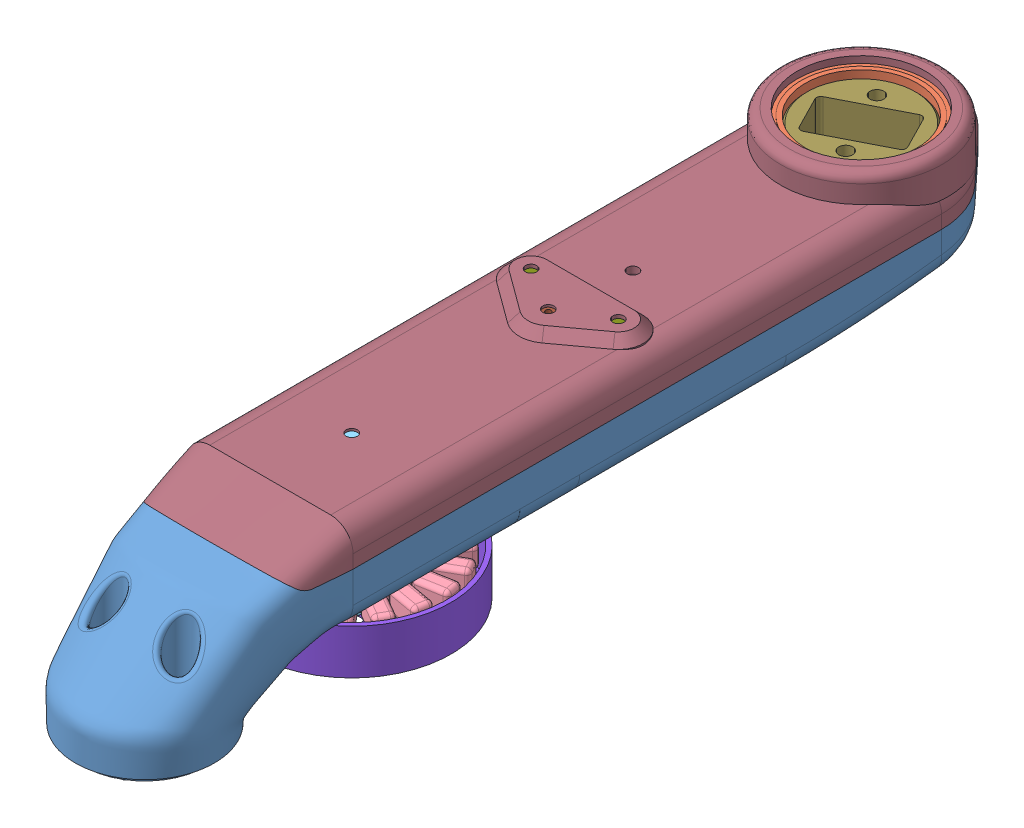
SolidWorks assembly actuator core assembly, configuration Default. Lengths in mm.
Overall size (62.38 43.94 198.25).
27 component instances, 16 part files, 38 mates.
Components (placement in the parent):
- upper limb base-1: upper limb base [Default] at (70.7092 92.7911 149.0007) size (42.52 37.51 198.25)
  - upper leg module shell base-1: upper leg module shell base [Default] x (-1 0 0) z (0 0 -1) size (37.02 37.51 198.25)
  - bearing 32x25x4mm-1: bearing 32x25x4mm [Default] at (0 0.5 -61) x (0.90658 0 0.422034) z (-0.422034 0 0.90658) size (32 4 32)
  - bearing 8mm x 3mm x 3mm-1: bearing 8mm x 3mm x 3mm [Default] at (0 -1.5 8.9) x (1 0 0) z (0 -1 0) size (7.96 7.96 3)
- motor rotor-1: motor rotor [Default] at (70.7092 85.0911 201.8007) x (0 0 -1) z (-1 0 0) size (40 13.5 39.72)
- motor assembly-2: motor assembly [Default] at (70.7092 72.4911 201.8007) x (-0.761097 0 -0.648639) z (-0.648639 0 0.761097) size (16.67 33.4 16.67)
  - motor shaft-1: motor shaft [Default] x (1 0 0) z (0 -1 0) size (3.99 3.99 33.4)
  - motor pulley-1: motor pulley [Default] at (0 -20.1 0) x (1 0 0) z (0 -1 0) size (8.98 9.1 6.7)
  - encoder wheel mount-1: encoder wheel mount [Default] at (0 -28.3 0) x (-0.562764 0 0.826618) z (-0.826618 0 -0.562764) size (12 5.96 12)
- motor stator-1: motor stator [Default] at (70.7092 85.0911 201.8007) x (0.629554 0 -0.776957) z (0 -1 0) size (44.35 44.35 16.24)
- B18.6.7M - M3 x 0.5 x 5 Type I Cross Recessed FHMS --5S-1: B18.6.7M - M3 x 0.5 x 5 Type I Cross Recessed FHMS --5S [B18.6.7M - M3 x 0.5 x 5 Type I Cross Recessed FHMS --5S] at (83.2092 94.5911 201.8007) x (0 -1 0) z (-0.166423 0 0.986054) size (5 5.5 5.5)
- B18.6.7M - M3 x 0.5 x 5 Type I Cross Recessed FHMS --5S-2: B18.6.7M - M3 x 0.5 x 5 Type I Cross Recessed FHMS --5S [B18.6.7M - M3 x 0.5 x 5 Type I Cross Recessed FHMS --5S] at (70.7092 94.5911 214.3007) x (0 -1 0) z (0.029806 0 0.999556) size (5 5.5 5.5)
- B18.6.7M - M3 x 0.5 x 5 Type I Cross Recessed FHMS --5S-3: B18.6.7M - M3 x 0.5 x 5 Type I Cross Recessed FHMS --5S [B18.6.7M - M3 x 0.5 x 5 Type I Cross Recessed FHMS --5S] at (58.2092 94.5911 201.8007) x (0 -1 0) z (0.999629 0 -0.027231) size (5 5.5 5.5)
- B18.6.7M - M3 x 0.5 x 5 Type I Cross Recessed FHMS --5S-4: B18.6.7M - M3 x 0.5 x 5 Type I Cross Recessed FHMS --5S [B18.6.7M - M3 x 0.5 x 5 Type I Cross Recessed FHMS --5S] at (70.7092 94.5911 189.3007) x (0 -1 0) z (-0.93368 0 0.358107) size (5 5.5 5.5)
- centre pulley-1: centre pulley [Default] at (66.4357 80.4446 131.9015) x (0.990944 0 0.134278) z (-0.134278 0 0.990944) size (30 19 30)
  - transmission pulley centre-1: transmission pulley centre [Default] at (7.726 11.8465 25.1899) size (30 6.8 30)
  - centre pulley-1: centre pulley [Default] at (7.726 25.3465 25.1899) x (0.694658 0 -0.71934) z (0 -1 0) size (8.98 9.1 19)
- transmission pulley output-1: transmission pulley output [Default] at (70.7092 97.7911 88.0007) x (-0.454924 0 -0.89053) z (0.89053 0 -0.454924) size (29 16.4 29)
- upper leg module cover-1: upper leg module cover [Default] at (70.7092 98.7911 142.6299) x (0 0 1) z (-1 0 0) size (170.23 17.96 37.06)
- bearing 32x25x4mm-1: bearing 32x25x4mm [Default] at (70.7092 107.2911 88.0007) size (32 4 32)
- bearing 8mm x 3mm x 3mm-1: bearing 8mm x 3mm x 3mm [Default] at (70.7092 107.2911 157.9007) x (1 0 0) z (0 -1 0) size (7.96 7.96 3)
- transmission belt tension roller-1: transmission belt tension roller [Default] at (60.9592 99.8911 152.0007) x (0.454066 0 0.890968) z (-0.890968 0 0.454066) size (10 4 10)
- bearing 7mm x 3mm x 3mm-2: bearing 7mm x 3mm x 3mm [Default] at (60.9592 103.8911 152.0007) x (0.030533 0 0.999534) z (0 -1 0) size (7 7 3)
- transmission belt tension roller-2: transmission belt tension roller [Default] at (80.4592 99.8911 152.0007) x (0.177081 0 -0.984196) z (0.984196 0 0.177081) size (10 4 10)
- bearing 7mm x 3mm x 3mm-3: bearing 7mm x 3mm x 3mm [Default] at (80.4592 103.8911 152.0007) x (0 0 -1) z (0 -1 0) size (7 7 3)
- flat head screw_am-1: flat head screw_am [B18.6.7M - M3 x 0.5 x 8 Type I Cross Recessed FHMS --8S] at (60.9592 100.0411 152.0007) x (0 1 0) z (0.851744 0 -0.523958) size (8 5.5 5.5)
- flat head screw_am-2: flat head screw_am [B18.6.7M - M3 x 0.5 x 8 Type I Cross Recessed FHMS --8S] at (80.4592 100.0411 152.0007) x (0 1 0) z (0.851744 0 -0.523958) size (8 5.5 5.5)
Mates (geometry in assembly coordinates):
- Concentric1: concentric aligned: cylinder of upper limb base-1/upper leg module shell base-1 through (70.7092 93.0911 201.8007) axis (0 -1 0) radius 15.25; cylinder of motor rotor-1 through (70.7092 92.5911 201.8007) axis (0 -1 0) radius 15
- Concentric2: concentric anti-aligned: cylinder of upper limb base-1/upper leg module shell base-1 through (70.7092 64.5911 189.3007) axis (0 1 0) radius 1.6; cylinder of motor rotor-1 through (70.7092 92.5911 189.3007) axis (0 -1 0) radius 2
- Coincident1: coincident anti-aligned: plane of upper limb base-1/upper leg module shell base-1 through (70.7092 92.5911 201.8007) normal (0 -1 0); plane of motor rotor-1 through (70.7092 92.5911 201.8007) normal (0 1 0)
- Concentric3: concentric aligned: line of motor rotor-1 through (70.7092 92.5911 201.8007) axis (0 -1 0); cylinder of motor assembly-2/motor shaft-1 through (70.7092 105.8911 201.8007) axis (0 -1 0) radius 1.995
- Coincident2: coincident anti-aligned: plane of motor rotor-1 through (70.7092 92.5911 201.8007) normal (0 1 0); plane of motor assembly-2/motor pulley-1 through (70.7092 92.5911 201.8007) normal (0 -1 0)
- Concentric4: concentric aligned: cylinder of motor assembly-2/motor shaft-1 through (70.7092 105.8911 201.8007) axis (0 -1 0) radius 1.995; cylinder of motor stator-1 through (70.7092 75.0911 201.8007) axis (0 -1 0) radius 2
- Coincident3: coincident aligned: plane of motor rotor-1 through (70.7092 85.0911 201.8007) normal (0 1 0); plane of motor stator-1 through (70.7092 85.0911 201.8007) normal (0 1 0)
- Concentric5: concentric anti-aligned: cylinder of motor rotor-1 through (70.7092 92.5911 189.3007) axis (0 -1 0) radius 2; cylinder of B18.6.7M - M3 x 0.5 x 5 Type I Cross Recessed FHMS --5S-4 through (70.7092 100.9411 189.3007) axis (0 1 0) radius 1.5
- Concentric6: concentric anti-aligned: cylinder of motor rotor-1 through (58.2092 92.5911 201.8007) axis (0 -1 0) radius 2; cylinder of B18.6.7M - M3 x 0.5 x 5 Type I Cross Recessed FHMS --5S-3 through (58.2092 100.9411 201.8007) axis (0 1 0) radius 1.5
- Concentric7: concentric anti-aligned: cylinder of motor rotor-1 through (70.7092 92.5911 214.3007) axis (0 -1 0) radius 2; cylinder of B18.6.7M - M3 x 0.5 x 5 Type I Cross Recessed FHMS --5S-2 through (70.7092 100.9411 214.3007) axis (0 1 0) radius 1.5
- Concentric8: concentric anti-aligned: cylinder of motor rotor-1 through (83.2092 92.5911 201.8007) axis (0 -1 0) radius 2; cylinder of B18.6.7M - M3 x 0.5 x 5 Type I Cross Recessed FHMS --5S-1 through (83.2092 100.9411 201.8007) axis (0 1 0) radius 1.5
- Coincident4: coincident aligned: plane of upper limb base-1/upper leg module shell base-1 through (70.7092 94.5911 201.8007) normal (0 1 0); plane of B18.6.7M - M3 x 0.5 x 5 Type I Cross Recessed FHMS --5S-4 through (70.7092 94.5911 189.3007) normal (0 1 0)
- Coincident5: coincident aligned: plane of upper limb base-1/upper leg module shell base-1 through (70.7092 94.5911 201.8007) normal (0 1 0); plane of B18.6.7M - M3 x 0.5 x 5 Type I Cross Recessed FHMS --5S-3 through (58.2092 94.5911 201.8007) normal (0 1 0)
- Coincident6: coincident aligned: plane of upper limb base-1/upper leg module shell base-1 through (70.7092 94.5911 201.8007) normal (0 1 0); plane of B18.6.7M - M3 x 0.5 x 5 Type I Cross Recessed FHMS --5S-1 through (83.2092 94.5911 201.8007) normal (0 1 0)
- Coincident7: coincident aligned: plane of upper limb base-1/upper leg module shell base-1 through (70.7092 94.5911 201.8007) normal (0 1 0); plane of B18.6.7M - M3 x 0.5 x 5 Type I Cross Recessed FHMS --5S-2 through (70.7092 94.5911 214.3007) normal (0 1 0)
- Concentric9: concentric anti-aligned: line of upper limb base-1/bearing 8mm x 3mm x 3mm-1 through (70.7092 91.0911 157.9007) axis (0 -1 0); cylinder of centre pulley-1/centre pulley-1 through (70.7092 89.2911 157.9007) axis (0 1 0) radius 1.995
- Coincident9: coincident anti-aligned: plane of upper limb base-1/bearing 8mm x 3mm x 3mm-1 through (70.7092 91.2911 157.9007) normal (0 1 0); plane of centre pulley-1/centre pulley-1 through (70.7092 91.2911 157.9007) normal (0 -1 0)
- Concentric11: concentric anti-aligned: cylinder of upper limb base-1/bearing 32x25x4mm-1 through (70.7092 97.2911 88.0007) axis (0 -1 0) radius 12.5; cylinder of transmission pulley output-1 through (70.7092 93.4411 88.0007) axis (0 1 0) radius 12.575
- Coincident12: coincident anti-aligned: plane of upper limb base-1/bearing 32x25x4mm-1 through (70.7092 97.2911 88.0007) normal (0 1 0); plane of transmission pulley output-1 through (70.7092 97.2911 88.0007) normal (0 -1 0)
- Concentric12: concentric aligned: circle of upper limb base-1/bearing 32x25x4mm-1; cylinder of upper leg module cover-1 through (70.7092 87.7911 88.0007) axis (0 1 0) radius 14.25
- Coincident20: coincident aligned: plane of upper limb base-1/upper leg module shell base-1 through (89.2092 86.7911 109.0007) normal (1 0 0); plane of upper leg module cover-1 through (89.2092 106.7911 219.9999) normal (1 0 0)
- Coincident24: coincident anti-aligned: plane of upper leg module cover-1 through (70.7092 107.2911 157.9007) normal (0 -1 0); plane of bearing 8mm x 3mm x 3mm-1 through (70.7092 107.2911 157.9007) normal (0 1 0)
- Concentric16: concentric anti-aligned: cylinder of upper leg module cover-1 through (70.7092 107.2911 157.9007) axis (0 -1 0) radius 3.98; cylinder of bearing 8mm x 3mm x 3mm-1 through (70.7092 104.2911 157.9007) axis (0 1 0) radius 3.98
- Concentric17: concentric anti-aligned: cylinder of upper leg module cover-1 through (70.7092 100.7911 88.0007) axis (0 1 0) radius 16.4954; cylinder of bearing 32x25x4mm-1 through (70.7092 111.2911 88.0007) axis (0 -1 0) radius 16
- Coincident25: coincident anti-aligned: plane of upper leg module cover-1 through (70.7092 111.2911 88.0007) normal (0 -1 0); plane of bearing 32x25x4mm-1 through (70.7092 111.2911 88.0007) normal (0 1 0)
- Concentric18: concentric anti-aligned: cylinder of transmission belt tension roller-1 through (60.9592 103.8911 152.0007) axis (0 -1 0) radius 3.5; cylinder of bearing 7mm x 3mm x 3mm-2 through (60.9592 100.8911 152.0007) axis (0 1 0) radius 3.5
- Coincident29: coincident anti-aligned: plane of transmission belt tension roller-1 through (60.9592 100.8911 152.0007) normal (0 1 0); plane of bearing 7mm x 3mm x 3mm-2 through (60.9592 100.8911 152.0007) normal (0 -1 0)
- Coincident30: coincident anti-aligned: plane of upper leg module cover-1 through (60.9592 103.8911 152.0007) normal (0 -1 0); plane of transmission belt tension roller-1 through (60.9592 103.8911 152.0007) normal (0 1 0)
- Concentric19: concentric anti-aligned: cylinder of upper leg module cover-1 through (60.9592 103.8911 152.0007) axis (0 1 0) radius 4; cylinder of transmission belt tension roller-1 through (60.9592 103.8911 152.0007) axis (0 -1 0) radius 5
- Concentric20: concentric anti-aligned: cylinder of transmission belt tension roller-2 through (80.4592 103.8911 152.0007) axis (0 -1 0) radius 3.5; cylinder of bearing 7mm x 3mm x 3mm-3 through (80.4592 100.8911 152.0007) axis (0 1 0) radius 3.5
- Coincident31: coincident anti-aligned: plane of transmission belt tension roller-2 through (80.4592 100.8911 152.0007) normal (0 1 0); plane of bearing 7mm x 3mm x 3mm-3 through (80.4592 100.8911 152.0007) normal (0 -1 0)
- Coincident33: coincident anti-aligned: plane of upper leg module cover-1 through (80.4592 103.8911 152.0007) normal (0 -1 0); plane of bearing 7mm x 3mm x 3mm-3 through (80.4592 103.8911 152.0007) normal (0 1 0)
- Concentric22: concentric anti-aligned: cylinder of upper leg module cover-1 through (80.4592 103.8911 152.0007) axis (0 1 0) radius 4; cylinder of transmission belt tension roller-2 through (80.4592 103.8911 152.0007) axis (0 -1 0) radius 5
- Concentric23: concentric anti-aligned: cylinder of bearing 7mm x 3mm x 3mm-2 through (60.9592 100.8911 152.0007) axis (0 1 0) radius 1.5; cylinder of flat head screw_am-1 through (60.9592 93.6911 152.0007) axis (0 -1 0) radius 1.5
- Coincident34: coincident aligned: cone of transmission belt tension roller-1 through (60.9592 100.4911 152.0007) axis (0 1 0); cone of flat head screw_am-1 through (60.9592 100.4911 152.0007) axis (0 1 0)
- Concentric24: concentric anti-aligned: cylinder of bearing 7mm x 3mm x 3mm-3 through (80.4592 100.8911 152.0007) axis (0 1 0) radius 1.5; cylinder of flat head screw_am-2 through (80.4592 93.6911 152.0007) axis (0 -1 0) radius 1.5
- Coincident35: coincident aligned: cone of transmission belt tension roller-2 through (80.4592 100.4911 152.0007) axis (0 1 0); cone of flat head screw_am-2 through (80.4592 100.4911 152.0007) axis (0 1 0)
- Coincident36: coincident anti-aligned: plane of upper limb base-1/upper leg module shell base-1 through (52.2092 98.7911 109.0007) normal (0 1 0); plane of upper leg module cover-1 through (70.7092 98.7911 142.6299) normal (0 -1 0)
